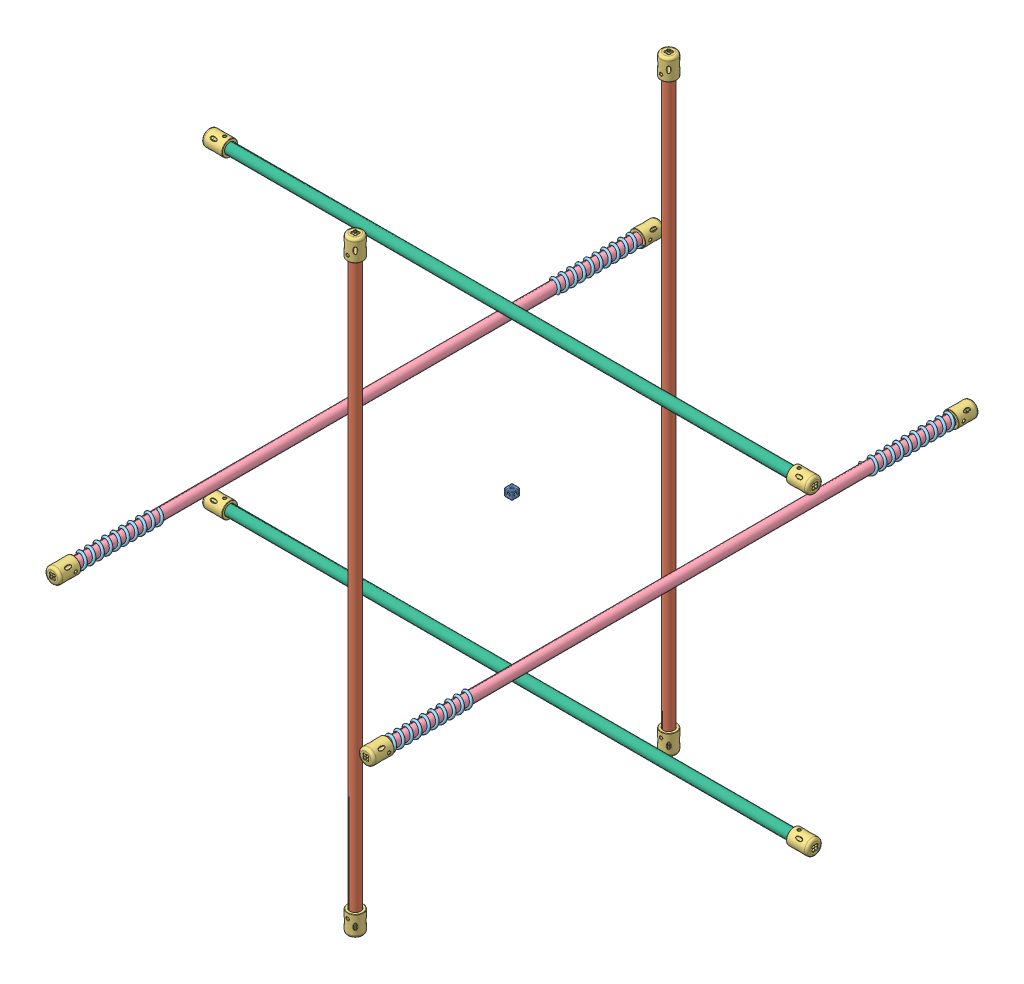
SolidWorks assembly 球形张拉整体装配, configuration Default. Lengths in mm.
Overall size (464.07 464.07 464.07).
30 component instances, 7 part files, 20 mates.
Components (placement in the parent):
- 虚拟中心-1: 虚拟中心 [默认] at origin size (6 6 6) (hidden)
- 前后拉杆装配-1: 前后拉杆装配 [Default] at (0 0 120) x (1 0 0) z (0 -1 0) size (17.54 17.55 464.07)
  - 前后碳纤拉杆-1: 前后碳纤拉杆 [默认] at origin size (8 8 450)
  - 拉杆绳索接头-1: 拉杆绳索接头 [默认] at (0 0 216) x (0.707107 -0.707107 0) z (-0.707107 -0.707107 0) size (12.41 16.03 12.39)
  - 拉杆绳索接头-2: 拉杆绳索接头 [默认] at (0 0 -216) x (0.707107 0.707107 0) z (-0.707107 0.707107 0) size (12.41 16.03 12.39)
- 前后拉杆装配-2: 前后拉杆装配 [Default] at (0 0 -120) x (1 0 0) z (0 1 0) size (17.54 17.55 464.07)
  - 前后碳纤拉杆-1: 前后碳纤拉杆 [默认] at origin size (8 8 450)
  - 拉杆绳索接头-1: 拉杆绳索接头 [默认] at (0 0 216) x (0.707107 -0.707107 0) z (-0.707107 -0.707107 0) size (12.41 16.03 12.39)
  - 拉杆绳索接头-2: 拉杆绳索接头 [默认] at (0 0 -216) x (0.707107 0.707107 0) z (-0.707107 0.707107 0) size (12.41 16.03 12.39)
- 左右拉杆装配-1: 左右拉杆装配 [Default] at (120 0 0) x (0 1 0) z (0 0 -1) size (17.54 17.55 464.07)
  - 左右碳纤拉杆-1: 左右碳纤拉杆 [默认] at origin size (8 8 450)
  - 拉杆绳索接头-1: 拉杆绳索接头 [默认] at (0 0 216) x (0.707107 -0.707107 0) z (-0.707107 -0.707107 0) size (12.41 16.03 12.39)
  - 拉杆绳索接头-2: 拉杆绳索接头 [默认] at (0 0 -216) x (0.707107 0.707107 0) z (-0.707107 0.707107 0) size (12.41 16.03 12.39)
  - 拉杆压簧-1: 拉杆压簧 [默认] at (0 0 -216) x (0 -1 0) z (-1 0 0) size (11.28 69 11)
  - 拉杆压簧-2: 拉杆压簧 [默认] at (0 0 216) x (-0.923728 -0.383049 0) z (0.383049 -0.923728 0) size (11.28 69 11)
- 左右拉杆装配-2: 左右拉杆装配 [Default] at (-120 0 0) x (0 -1 0) z (0 0 -1) size (17.54 17.55 464.07)
  - 左右碳纤拉杆-1: 左右碳纤拉杆 [默认] at origin size (8 8 450)
  - 拉杆绳索接头-1: 拉杆绳索接头 [默认] at (0 0 216) x (0.707107 -0.707107 0) z (-0.707107 -0.707107 0) size (12.41 16.03 12.39)
  - 拉杆绳索接头-2: 拉杆绳索接头 [默认] at (0 0 -216) x (0.707107 0.707107 0) z (-0.707107 0.707107 0) size (12.41 16.03 12.39)
  - 拉杆压簧-1: 拉杆压簧 [默认] at (0 0 -216) x (0 -1 0) z (-1 0 0) size (11.28 69 11)
  - 拉杆压簧-2: 拉杆压簧 [默认] at (0 0 216) x (-0.923728 -0.383049 0) z (0.383049 -0.923728 0) size (11.28 69 11)
- 上下拉杆装配-1: 上下拉杆装配 [Default] at (0 120 0) x (0 0 1) z (-1 0 0) size (17.54 17.55 464.07)
  - 上下碳纤拉杆-1: 上下碳纤拉杆 [默认] at origin size (8 8 450)
  - 拉杆绳索接头-1: 拉杆绳索接头 [默认] at (0 0 216) x (0.707107 -0.707107 0) z (-0.707107 -0.707107 0) size (12.41 16.03 12.39)
  - 拉杆绳索接头-2: 拉杆绳索接头 [默认] at (0 0 -216) x (0.707107 0.707107 0) z (-0.707107 0.707107 0) size (12.41 16.03 12.39)
- 上下拉杆装配-2: 上下拉杆装配 [Default] at (0 -120 0) x (0 0 1) z (1 0 0) size (17.54 17.55 464.07)
  - 上下碳纤拉杆-1: 上下碳纤拉杆 [默认] at origin size (8 8 450)
  - 拉杆绳索接头-1: 拉杆绳索接头 [默认] at (0 0 216) x (0.707107 -0.707107 0) z (-0.707107 -0.707107 0) size (12.41 16.03 12.39)
  - 拉杆绳索接头-2: 拉杆绳索接头 [默认] at (0 0 -216) x (0.707107 0.707107 0) z (-0.707107 0.707107 0) size (12.41 16.03 12.39)
- 绳索^球形张拉整体装配-1: 绳索^球形张拉整体装配 [默认] at origin size (464 464 464) (virtual)
Mates (geometry in assembly coordinates):
- 重合1: coordinate: point of 虚拟中心-1
- 同心1: concentric anti-aligned: cylinder of 虚拟中心-1 through (0 0 -3) axis (0 0 1) radius 1; circle of 前后拉杆装配-2/碳纤拉杆-1
- 平行1: parallel anti-aligned: cylinder of 前后拉杆装配-1/碳纤拉杆-1 through (0 225 120) axis (0 -1 0) radius 3; cylinder of 虚拟中心-1 through (0 -3 0) axis (0 1 0) radius 1
- 同心3: concentric aligned: cylinder of 虚拟中心-1 through (0 0 -3) axis (0 0 1) radius 1; circle of 前后拉杆装配-1/碳纤拉杆-1
- 平行2: parallel aligned: cylinder of 前后拉杆装配-2/碳纤拉杆-1 through (0 -225 -120) axis (0 1 0) radius 4; cylinder of 虚拟中心-1 through (0 -3 0) axis (0 1 0) radius 1
- 同心4: concentric aligned: cylinder of 虚拟中心-1 through (-3 0 0) axis (1 0 0) radius 1; circle of 左右拉杆装配-1/左右碳纤拉杆-1
- 平行3: parallel anti-aligned: cylinder of 左右拉杆装配-1/左右碳纤拉杆-1 through (120 0 225) axis (0 0 -1) radius 4; cylinder of 虚拟中心-1 through (0 0 -3) axis (0 0 1) radius 1
- 平行4: parallel anti-aligned: cylinder of 左右拉杆装配-2/左右碳纤拉杆-1 through (-120 0 225) axis (0 0 -1) radius 4; cylinder of 虚拟中心-1 through (0 0 -3) axis (0 0 1) radius 1
- 同心7: concentric anti-aligned: cylinder of 虚拟中心-1 through (-3 0 0) axis (1 0 0) radius 1; circle of 左右拉杆装配-2/左右碳纤拉杆-1
- 平行5: parallel anti-aligned: cylinder of 上下拉杆装配-1/碳纤拉杆-1 through (225 120 0) axis (-1 0 0) radius 4; cylinder of 虚拟中心-1 through (-3 0 0) axis (1 0 0) radius 1
- 平行6: parallel aligned: cylinder of 上下拉杆装配-2/碳纤拉杆-1 through (-225 -120 0) axis (1 0 0) radius 4; cylinder of 虚拟中心-1 through (-3 0 0) axis (1 0 0) radius 1
- 同心10: concentric aligned: cylinder of 虚拟中心-1 through (0 -3 0) axis (0 1 0) radius 1; circle of 上下拉杆装配-1/碳纤拉杆-1
- 同心11: concentric anti-aligned: cylinder of 虚拟中心-1 through (0 -3 0) axis (0 1 0) radius 1; circle of 上下拉杆装配-2/碳纤拉杆-1
- 距离5: distance = 120 mm: cylinder of 上下拉杆装配-1/碳纤拉杆-1 through (225 120 0) axis (-1 0 0) radius 4; cylinder of 虚拟中心-1 through (0 0 -3) axis (0 0 1) radius 1
- 距离6: distance = 120 mm: cylinder of 虚拟中心-1 through (0 0 -3) axis (0 0 1) radius 1; cylinder of 上下拉杆装配-2/碳纤拉杆-1 through (-225 -120 0) axis (1 0 0) radius 4
- 距离7: distance = 120 mm: cylinder of 前后拉杆装配-1/碳纤拉杆-1 through (0 225 120) axis (0 -1 0) radius 4; cylinder of 虚拟中心-1 through (-3 0 0) axis (1 0 0) radius 1
- 距离8: distance = 120 mm: cylinder of 虚拟中心-1 through (-3 0 0) axis (1 0 0) radius 1; cylinder of 前后拉杆装配-2/碳纤拉杆-1 through (0 -225 -120) axis (0 1 0) radius 4
- 距离9: distance = 120 mm: cylinder of 左右拉杆装配-1/左右碳纤拉杆-1 through (120 0 225) axis (0 0 -1) radius 4; cylinder of 虚拟中心-1 through (0 0 -3) axis (0 0 1) radius 1
- 距离10: distance = 120 mm: cylinder of 虚拟中心-1 through (0 0 -3) axis (0 0 1) radius 1; cylinder of 左右拉杆装配-2/左右碳纤拉杆-1 through (-120 0 225) axis (0 0 -1) radius 4
- 重合9: coordinate: unknown of 绳索^张拉整体装配-1
